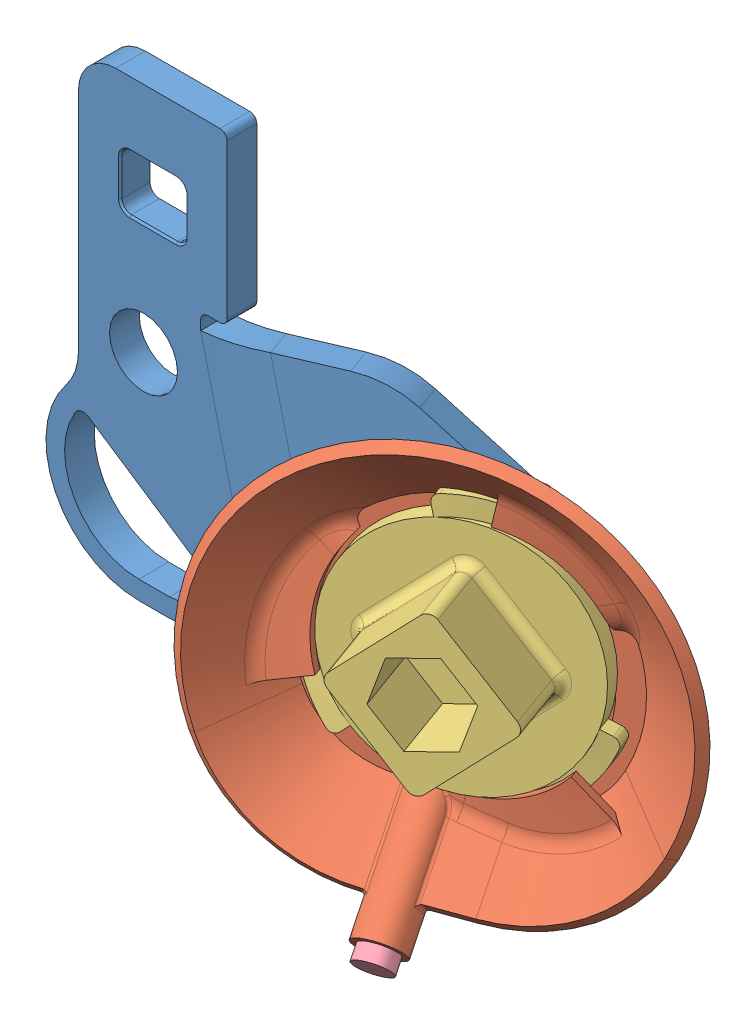
SolidWorks assembly 0160-041-00, configuration Default. Lengths in mm.
Overall size (32.25 31.53 13.82).
4 component instances, 4 part files, 6 mates.
Components (placement in the parent):
- 0160-100-10-1: 0160-100-10 [Default] at origin size (25.86 26.22 7.27)
- 0160-200-45-1: 0160-200-45 [Default] at origin size (20.2 22.52 12.64)
- 0160-200-37-1: 0160-200-37 [Default] at (4.1249 -0.2296 2.1759) x (0.654668 -0.727736 -0.204472) z (-0.645997 -0.679085 0.348613) size (13.49 5.53 14.16)
- mill-max-3024-0-01-15-00-00-03-0-1: mill-max-3024-0-01-15-00-00-03-0 [Pin] at (4.7758 -11.8994 7.8703) x (-0.277577 0.635253 -0.720697) z (0.927983 -0.016826 -0.372244) size (7.37 1.83 1.83)
Mates (geometry in assembly coordinates):
- Coincident9: coincident anti-aligned: plane of 0160-200-37-1 through (3.9385 -0.2753 1.7414) normal (-0.392552 -0.096138 -0.914691); plane of 0160-200-45-1 through (9.4569 -1.2674 -0.5226) normal (0.392552 0.096138 0.914691)
- Coincident11: coordinate: point of 0160-100-10-1
- Coincident12: coordinate: unknown of 0160-200-45-1
- Concentric8: concentric anti-aligned: line of 0160-200-45-1 through (3.9385 -0.2753 1.7414) axis (0.392552 0.096138 0.914691); cylinder of 0160-200-37-1 through (4.3408 -0.1767 2.679) axis (-0.392552 -0.096138 -0.914691) radius 6
- Concentric10: concentric aligned: cylinder of 0160-200-45-1 through (1.7371 -4.9452 -0.0193) axis (0.277577 -0.635253 0.720697) radius 0.7112; cylinder of mill-max-3024-0-01-15-00-00-03-0-1 through (4.7758 -11.8994 7.8703) axis (0.277577 -0.635253 0.720697) radius 0.6731
- Coincident13: coincident anti-aligned: plane of 0160-200-45-1 through (3.8221 -8.7471 9.9236) normal (0.277577 -0.635253 0.720697); plane of mill-max-3024-0-01-15-00-00-03-0-1 through (4.7845 -10.6932 7.8376) normal (-0.277577 0.635253 -0.720697)
